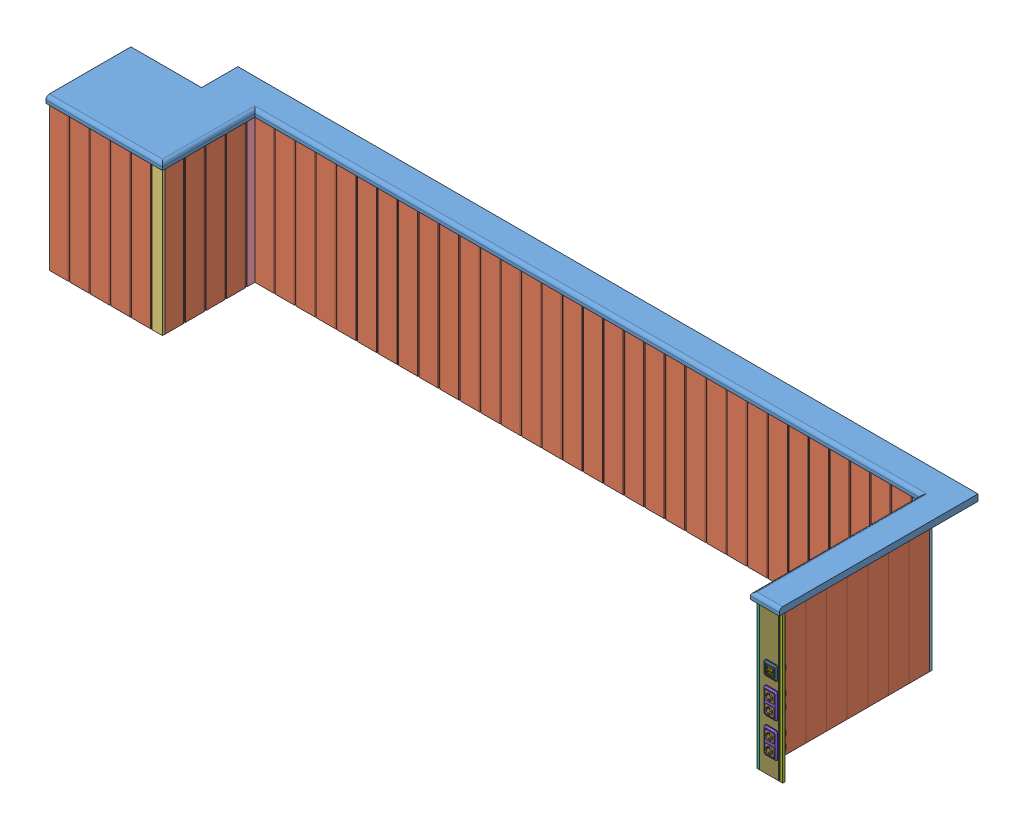
SolidWorks assembly Brüstung, configuration Standard. Lengths in mm.
Overall size (4774 900 1170).
129 component instances, 30 part files, 185 mates.
Components (placement in the parent):
- Platte-1: Platte [Standard] at (1989.1315 795.0064 4189) size (4774 38 1170)
- Wandbrett-1: Wandbrett [Standard] at (-2724.3685 795.0064 4876) x (1 0 0) z (0 0 -1) size (131 862 14)
- Wandbrett-2: Wandbrett [Standard] at (-2603.3685 795.0064 4876) x (1 0 0) z (0 0 -1) size (131 862 14)
- Wandbrett-3: Wandbrett [Standard] at (-2482.3685 795.0064 4876) x (1 0 0) z (0 0 -1) size (131 862 14)
- Wandbrett-4: Wandbrett [Standard] at (-2361.3685 795.0064 4876) x (1 0 0) z (0 0 -1) size (131 862 14)
- Wandbrett-Ecke1-1: Wandbrett-Ecke1 [Standard] at (-2119.3685 795.0064 4876) x (1 0 0) z (0 0 -1) size (61 862 14)
- Wandbrett-6: Wandbrett [Standard] at (-2125.8685 795.0064 4808.5) x (0 0 -1) z (-1 0 0) size (131 862 14)
- Wandbrett-7: Wandbrett [Standard] at (-2125.8685 795.0064 4687.5) x (0 0 -1) z (-1 0 0) size (131 862 14)
- Wandbrett-8: Wandbrett [Standard] at (-2125.8685 795.0064 4566.5) x (0 0 -1) z (-1 0 0) size (131 862 14)
- Wandbrett-9: Wandbrett [Standard] at (-2125.8685 795.0064 4445.5) x (0 0 -1) z (-1 0 0) size (131 862 14)
- Wandbrett-Ecke2-1: Wandbrett-Ecke2 [Standard] at (-2125.8685 795.0064 4324.5) x (0 0 -1) z (-1 0 0) size (60 862 14)
- Wandbrett-11: Wandbrett [Standard] at (-2058.3685 795.0064 4332) x (1 0 0) z (0 0 -1) size (131 862 14)
- Wandbrett-12: Wandbrett [Standard] at (-1937.3685 795.0064 4332) x (1 0 0) z (0 0 -1) size (131 862 14)
- Wandbrett-13: Wandbrett [Standard] at (-1816.3685 795.0064 4332) x (1 0 0) z (0 0 -1) size (131 862 14)
- Wandbrett-14: Wandbrett [Standard] at (-1695.3685 795.0064 4332) x (1 0 0) z (0 0 -1) size (131 862 14)
- Wandbrett-15: Wandbrett [Standard] at (-1574.3685 795.0064 4332) x (1 0 0) z (0 0 -1) size (131 862 14)
- Wandbrett-16: Wandbrett [Standard] at (-1453.3685 795.0064 4332) x (1 0 0) z (0 0 -1) size (131 862 14)
- Wandbrett-17: Wandbrett [Standard] at (-1332.3685 795.0064 4332) x (1 0 0) z (0 0 -1) size (131 862 14)
- Wandbrett-18: Wandbrett [Standard] at (-1211.3685 795.0064 4332) x (1 0 0) z (0 0 -1) size (131 862 14)
- Wandbrett-19: Wandbrett [Standard] at (-1090.3685 795.0064 4332) x (1 0 0) z (0 0 -1) size (131 862 14)
- Wandbrett-20: Wandbrett [Standard] at (-969.3685 795.0064 4332) x (1 0 0) z (0 0 -1) size (131 862 14)
- Wandbrett-21: Wandbrett [Standard] at (-848.3685 795.0064 4332) x (1 0 0) z (0 0 -1) size (131 862 14)
- Wandbrett-22: Wandbrett [Standard] at (-727.3685 795.0064 4332) x (1 0 0) z (0 0 -1) size (131 862 14)
- Wandbrett-23: Wandbrett [Standard] at (-606.3685 795.0064 4332) x (1 0 0) z (0 0 -1) size (131 862 14)
- Wandbrett-24: Wandbrett [Standard] at (-485.3685 795.0064 4332) x (1 0 0) z (0 0 -1) size (131 862 14)
- Wandbrett-25: Wandbrett [Standard] at (-364.3685 795.0064 4332) x (1 0 0) z (0 0 -1) size (131 862 14)
- Wandbrett-26: Wandbrett [Standard] at (-243.3685 795.0064 4332) x (1 0 0) z (0 0 -1) size (131 862 14)
- Wandbrett-27: Wandbrett [Standard] at (-122.3685 795.0064 4332) x (1 0 0) z (0 0 -1) size (131 862 14)
- Wandbrett-28: Wandbrett [Standard] at (-1.3685 795.0064 4332) x (1 0 0) z (0 0 -1) size (131 862 14)
- Wandbrett-29: Wandbrett [Standard] at (119.6315 795.0064 4332) x (1 0 0) z (0 0 -1) size (131 862 14)
- Wandbrett-30: Wandbrett [Standard] at (240.6315 795.0064 4332) x (1 0 0) z (0 0 -1) size (131 862 14)
- Wandbrett-31: Wandbrett [Standard] at (361.6315 795.0064 4332) x (1 0 0) z (0 0 -1) size (131 862 14)
- Wandbrett-32: Wandbrett [Standard] at (482.6315 795.0064 4332) x (1 0 0) z (0 0 -1) size (131 862 14)
- Wandbrett-33: Wandbrett [Standard] at (603.6315 795.0064 4332) x (1 0 0) z (0 0 -1) size (131 862 14)
- Wandbrett-34: Wandbrett [Standard] at (724.6315 795.0064 4332) x (1 0 0) z (0 0 -1) size (131 862 14)
- Wandbrett-35: Wandbrett [Standard] at (845.6315 795.0064 4332) x (1 0 0) z (0 0 -1) size (131 862 14)
- Wandbrett-36: Wandbrett [Standard] at (966.6315 795.0064 4332) x (1 0 0) z (0 0 -1) size (131 862 14)
- Wandbrett-37: Wandbrett [Standard] at (1087.6315 795.0064 4332) x (1 0 0) z (0 0 -1) size (131 862 14)
- Wandbrett-38: Wandbrett [Standard] at (1208.6315 795.0064 4332) x (1 0 0) z (0 0 -1) size (131 862 14)
- Wandbrett-39: Wandbrett [Standard] at (1329.6315 795.0064 4332) x (1 0 0) z (0 0 -1) size (131 862 14)
- Wandbrett-40: Wandbrett [Standard] at (1450.6315 795.0064 4332) x (1 0 0) z (0 0 -1) size (131 862 14)
- Wandbrett-41: Wandbrett [Standard] at (1571.6315 795.0064 4332) x (1 0 0) z (0 0 -1) size (131 862 14)
- Wandbrett-42: Wandbrett [Standard] at (1692.6315 795.0064 4332) x (1 0 0) z (0 0 -1) size (131 862 14)
- Wandbrett-43: Wandbrett [Standard] at (-2240.3685 795.0064 4876) x (1 0 0) z (0 0 -1) size (131 862 14)
- Wandbrett-Ecke3-1: Wandbrett-Ecke3 [Standard] at (1813.6315 795.0064 4332) x (1 0 0) z (0 0 -1) size (100 862 14)
- Wandbrett-44: Wandbrett [Standard] at (1846.1315 795.0064 4399.5) x (0 0 1) z (1 0 0) size (131 862 14)
- Wandbrett-45: Wandbrett [Standard] at (1846.1315 795.0064 4520.5) x (0 0 1) z (1 0 0) size (131 862 14)
- Wandbrett-46: Wandbrett [Standard] at (1846.1315 795.0064 4641.5) x (0 0 1) z (1 0 0) size (131 862 14)
- Wandbrett-47: Wandbrett [Standard] at (1846.1315 795.0064 4762.5) x (0 0 1) z (1 0 0) size (131 862 14)
- Wandbrett-48: Wandbrett [Standard] at (1846.1315 795.0064 4883.5) x (0 0 1) z (1 0 0) size (131 862 14)
- Wandbrett-49: Wandbrett [Standard] at (1846.1315 795.0064 5004.5) x (0 0 1) z (1 0 0) size (131 862 14)
- Wandbrett-50: Wandbrett [Standard] at (1846.1315 795.0064 5125.5) x (0 0 1) z (1 0 0) size (131 862 14)
- Wandbrett-51: Wandbrett [Standard] at (1846.1315 795.0064 5246.5) x (0 0 1) z (1 0 0) size (131 862 14)
- Wandbrett-Ecke4-1: Wandbrett-Ecke4 [Standard] at (1846.1315 795.0064 5367.5) x (0 0 1) z (1 0 0) size (32 862 14)
- Wandbrett-Ecke5-1: Wandbrett-Ecke5 [Standard] at (2034.6315 795.0064 5332) x (1 0 0) z (0 0 -1) size (15 862 14)
- Steckdose_2er-1: Steckdose_2er [Standard] at (1873.2124 150.5045 5350) x (0 -1 0) z (0 0 1) size (152.53 80.54 48.85)
  - Wandplatte_2er-1: Wandplatte_2er [Standard] at origin size (152.53 80.54 11)
  - Steckdose-1: Steckdose [Standard] at (58.6803 128.1202 -10.7714) x (1 0 0) z (0 -1 0) size (71 48.85 71)
    - Montageplatte.02-1: Montageplatte.02 [Standard] at (-129.6803 11 128.1202) x (1 0 0) z (0 1 0) size (71 71 18.97)
    - Halter-1: Halter [Standard] at (-129.6803 11 128.1202) x (1 0 0) z (0 1 0) size (45.97 31.9 15.37)
    - Kralle.04-1: Kralle.04 [Standard] at (-126.9942 12.4168 128.1202) x (0.996195 -0.087156 0) z (0.087156 0.996195 0) size (8.78 9 23.36)
    - Kralle.04-2: Kralle.04 [Standard] at (21.6299 12.4168 26.282) x (-0.996195 -0.087156 0) z (-0.087156 0.996195 0) size (8.78 9 23.36)
    - Buchse-1: Buchse [Standard] at (-129.6803 10.7714 128.1202) x (1 0 0) z (0 1 0) size (64.03 64.03 27)
    - Stromklemme_1.02-1: Stromklemme_1.02 [Standard] at (-129.6803 11 127.9932) x (1 0 0) z (0 1 0) size (8.38 19.82 12.51)
    - Stromklemme_2.02-1: Stromklemme_2.02 [Standard] at (-129.6803 11 127.9932) x (1 0 0) z (0 1 0) size (8.38 19.82 12.51)
    - Erdleiter-1: Erdleiter [Standard] at (-129.6803 11 128.1202) x (1 0 0) z (0 1 0) size (7.24 44.01 27.12)
  - Steckdose-2: Steckdose [Standard] at (129.6803 128.1202 -10.7714) x (1 0 0) z (0 -1 0) size (71 48.85 71)
    - Montageplatte.02-1: Montageplatte.02 [Standard] at (-129.6803 11 128.1202) x (1 0 0) z (0 1 0) size (71 71 18.97)
    - Halter-1: Halter [Standard] at (-129.6803 11 128.1202) x (1 0 0) z (0 1 0) size (45.97 31.9 15.37)
    - Kralle.04-1: Kralle.04 [Standard] at (-126.9942 12.4168 128.1202) x (0.996195 -0.087156 0) z (0.087156 0.996195 0) size (8.78 9 23.36)
    - Kralle.04-2: Kralle.04 [Standard] at (21.6299 12.4168 26.282) x (-0.996195 -0.087156 0) z (-0.087156 0.996195 0) size (8.78 9 23.36)
    - Buchse-1: Buchse [Standard] at (-129.6803 10.7714 128.1202) x (1 0 0) z (0 1 0) size (64.03 64.03 27)
    - Stromklemme_1.02-1: Stromklemme_1.02 [Standard] at (-129.6803 11 127.9932) x (1 0 0) z (0 1 0) size (8.38 19.82 12.51)
    - Stromklemme_2.02-1: Stromklemme_2.02 [Standard] at (-129.6803 11 127.9932) x (1 0 0) z (0 1 0) size (8.38 19.82 12.51)
    - Erdleiter-1: Erdleiter [Standard] at (-129.6803 11 128.1202) x (1 0 0) z (0 1 0) size (7.24 44.01 27.12)
- Steckdose_1er-RJ-1: Steckdose_1er-RJ [Standard] at (1922.84 484.4291 5275.7349) x (0 -1 0) z (0 0 1) size (81 80 25.23)
  - Steckdose-RJ45-1: Steckdose-RJ45 [Standard] at (18.9082 -0.7233 10.2377) size (54 54 25.23)
    - Buchse-RJ45-1: Buchse-RJ45 [Standard] at (-88.9836 -48.9043 64.0274) size (54 54 6)
    - 65864-1: 65864 [Default] at (-11.8405 9.7148 53.1274) size (17.49 15.42 25.23)
      - 65864_01-1: 65864_01 [Default] at origin size (9.69 0.75 13.83)
      - 65864_02-1: 65864_02 [Default] at origin size (9.44 0.68 13.83)
      - 65864_03-1: 65864_03 [Default] at origin size (9.69 0.61 13.84)
      - 65864_04-1: 65864_04 [Default] at origin size (9.44 0.54 13.83)
      - 65864_05-1: 65864_05 [Default] at origin size (9.69 0.54 13.82)
      - 65864_06-1: 65864_06 [Default] at origin size (9.44 0.6 13.83)
      - 65864_07-1: 65864_07 [Default] at origin size (9.69 0.68 13.83)
      - 65864_08-1: 65864_08 [Default] at origin size (9.44 0.75 13.83)
      - 65864_09-1: 65864_09 [Default] at origin size (17.11 15.1 23.65)
      - 65864_10-1: 65864_10 [Default] at origin size (6.36 10.31 6.36)
      - 65864_11-1: 65864_11 [Default] at origin size (17.49 15.42 25.23)
    - 65864-2: 65864 [Default] at (-11.8405 -5.6852 53.1274) size (17.49 15.42 25.23)
      - 65864_01-1: 65864_01 [Default] at origin size (9.69 0.75 13.83)
      - 65864_02-1: 65864_02 [Default] at origin size (9.44 0.68 13.83)
      - 65864_03-1: 65864_03 [Default] at origin size (9.69 0.61 13.84)
      - 65864_04-1: 65864_04 [Default] at origin size (9.44 0.54 13.83)
      - 65864_05-1: 65864_05 [Default] at origin size (9.69 0.54 13.82)
      - 65864_06-1: 65864_06 [Default] at origin size (9.44 0.6 13.83)
      - 65864_07-1: 65864_07 [Default] at origin size (9.69 0.68 13.83)
      - 65864_08-1: 65864_08 [Default] at origin size (9.44 0.75 13.83)
      - 65864_09-1: 65864_09 [Default] at origin size (17.11 15.1 23.65)
      - 65864_10-1: 65864_10 [Default] at origin size (6.36 10.31 6.36)
      - 65864_11-1: 65864_11 [Default] at origin size (17.49 15.42 25.23)
  - Wandplatte_1er-1: Wandplatte_1er [Standard] at (0.9246 -49.6276 74.2651) size (81 80 11.01)
- Steckdose_2er-2: Steckdose_2er [Standard] at (1873.2124 352.5045 5350) x (0 -1 0) z (0 0 1) size (152.53 80.54 48.85)
  - Wandplatte_2er-1: Wandplatte_2er [Standard] at origin size (152.53 80.54 11)
  - Steckdose-1: Steckdose [Standard] at (58.6803 128.1202 -10.7714) x (1 0 0) z (0 -1 0) size (71 48.85 71)
    - Montageplatte.02-1: Montageplatte.02 [Standard] at (-129.6803 11 128.1202) x (1 0 0) z (0 1 0) size (71 71 18.97)
    - Halter-1: Halter [Standard] at (-129.6803 11 128.1202) x (1 0 0) z (0 1 0) size (45.97 31.9 15.37)
    - Kralle.04-1: Kralle.04 [Standard] at (-126.9942 12.4168 128.1202) x (0.996195 -0.087156 0) z (0.087156 0.996195 0) size (8.78 9 23.36)
    - Kralle.04-2: Kralle.04 [Standard] at (21.6299 12.4168 26.282) x (-0.996195 -0.087156 0) z (-0.087156 0.996195 0) size (8.78 9 23.36)
    - Buchse-1: Buchse [Standard] at (-129.6803 10.7714 128.1202) x (1 0 0) z (0 1 0) size (64.03 64.03 27)
    - Stromklemme_1.02-1: Stromklemme_1.02 [Standard] at (-129.6803 11 127.9932) x (1 0 0) z (0 1 0) size (8.38 19.82 12.51)
    - Stromklemme_2.02-1: Stromklemme_2.02 [Standard] at (-129.6803 11 127.9932) x (1 0 0) z (0 1 0) size (8.38 19.82 12.51)
    - Erdleiter-1: Erdleiter [Standard] at (-129.6803 11 128.1202) x (1 0 0) z (0 1 0) size (7.24 44.01 27.12)
  - Steckdose-2: Steckdose [Standard] at (129.6803 128.1202 -10.7714) x (1 0 0) z (0 -1 0) size (71 48.85 71)
    - Montageplatte.02-1: Montageplatte.02 [Standard] at (-129.6803 11 128.1202) x (1 0 0) z (0 1 0) size (71 71 18.97)
    - Halter-1: Halter [Standard] at (-129.6803 11 128.1202) x (1 0 0) z (0 1 0) size (45.97 31.9 15.37)
    - Kralle.04-1: Kralle.04 [Standard] at (-126.9942 12.4168 128.1202) x (0.996195 -0.087156 0) z (0.087156 0.996195 0) size (8.78 9 23.36)
    - Kralle.04-2: Kralle.04 [Standard] at (21.6299 12.4168 26.282) x (-0.996195 -0.087156 0) z (-0.087156 0.996195 0) size (8.78 9 23.36)
    - Buchse-1: Buchse [Standard] at (-129.6803 10.7714 128.1202) x (1 0 0) z (0 1 0) size (64.03 64.03 27)
    - Stromklemme_1.02-1: Stromklemme_1.02 [Standard] at (-129.6803 11 127.9932) x (1 0 0) z (0 1 0) size (8.38 19.82 12.51)
    - Stromklemme_2.02-1: Stromklemme_2.02 [Standard] at (-129.6803 11 127.9932) x (1 0 0) z (0 1 0) size (8.38 19.82 12.51)
    - Erdleiter-1: Erdleiter [Standard] at (-129.6803 11 128.1202) x (1 0 0) z (0 1 0) size (7.24 44.01 27.12)
- Hohlwanddose-1: Hohlwanddose [Standard] at (1924.1315 477.4581 5340) x (0 0 -1) z (1 0 0) size (60.7 71 71)
- Hohlwanddose-2: Hohlwanddose [Standard] at (1924.1315 346.5064 5340) x (0 0 -1) z (1 0 0) size (60.7 71 71)
- Hohlwanddose-3: Hohlwanddose [Standard] at (1924.1315 275.5064 5340) x (0 0 -1) z (1 0 0) size (60.7 71 71)
- Hohlwanddose-4: Hohlwanddose [Standard] at (1924.1315 144.5064 5340) x (0 0 -1) z (1 0 0) size (60.7 71 71)
- Hohlwanddose-5: Hohlwanddose [Standard] at (1924.1315 73.5064 5340) x (0 0 -1) z (1 0 0) size (60.7 71 71)
- Wandbrett-Dosen1-1: Wandbrett-Dosen1 [Standard] at (1913.6315 795.0064 5332) x (1 0 0) z (0 0 -1) size (131 862 14)
Mates (geometry in assembly coordinates):
- Deckungsgleich1: coincident anti-aligned: plane of Platte-1 through (1989.1315 795.0064 4189) normal (0 -1 0); plane of Wandbrett-1 through (-2674.8685 795.0064 4879) normal (0 1 0)
- Deckungsgleich2: coincident anti-aligned: plane of Platte-1 through (1989.1315 795.0064 4189) normal (0 -1 0); plane of Wandbrett-2 through (-2553.8685 795.0064 4879) normal (0 1 0)
- Deckungsgleich3: coincident anti-aligned: plane of Platte-1 through (1989.1315 795.0064 4189) normal (0 -1 0); plane of Wandbrett-3 through (-2432.8685 795.0064 4879) normal (0 1 0)
- Deckungsgleich4: coincident anti-aligned: plane of Platte-1 through (1989.1315 795.0064 4189) normal (0 -1 0); plane of Wandbrett-4 through (-2311.8685 795.0064 4879) normal (0 1 0)
- Parallel1: parallel aligned: plane of Platte-1 through (-2784.8685 833.0064 4903) normal (0 0 1); plane of Wandbrett-1 through (-2674.8685 -66.9936 4883) normal (0 0 1)
- Abstand2: distance = 20 mm aligned: plane of Wandbrett-1 through (-2674.8685 -66.9936 4883) normal (0 0 1); plane of Platte-1 through (-2784.8685 833.0064 4903) normal (0 0 1)
- Deckungsgleich9: coincident aligned: plane of Platte-1 through (-2784.8685 833.0064 4903) normal (-1 0 0); plane of Wandbrett-1 through (-2784.8685 -66.9936 4869) normal (-1 0 0)
- Deckungsgleich10: coincident anti-aligned: plane of Wandbrett-1 through (-2663.8685 -66.9936 4878) normal (0 0 1); plane of Wandbrett-2 through (-2653.8685 -66.9936 4878) normal (0 0 -1)
- Deckungsgleich11: coincident anti-aligned: plane of Wandbrett-2 through (-2542.8685 -66.9936 4878) normal (0 0 1); plane of Wandbrett-3 through (-2532.8685 -66.9936 4878) normal (0 0 -1)
- Deckungsgleich12: coincident anti-aligned: plane of Wandbrett-3 through (-2421.8685 -66.9936 4878) normal (0 0 1); plane of Wandbrett-4 through (-2411.8685 -66.9936 4878) normal (0 0 -1)
- Deckungsgleich14: coincident anti-aligned: plane of Wandbrett-1 through (-2653.8685 -66.9936 4878) normal (1 0 0); plane of Wandbrett-2 through (-2653.8685 -66.9936 4874) normal (-1 0 0)
- Deckungsgleich15: coincident anti-aligned: plane of Wandbrett-2 through (-2532.8685 -66.9936 4878) normal (1 0 0); plane of Wandbrett-3 through (-2532.8685 -66.9936 4874) normal (-1 0 0)
- Deckungsgleich16: coincident anti-aligned: plane of Wandbrett-3 through (-2411.8685 -66.9936 4878) normal (1 0 0); plane of Wandbrett-4 through (-2411.8685 -66.9936 4874) normal (-1 0 0)
- Deckungsgleich18: coincident anti-aligned: plane of Platte-1 through (1989.1315 795.0064 4189) normal (0 -1 0); plane of Wandbrett-Ecke1-1 through (-2069.8685 795.0064 4879) normal (0 1 0)
- Deckungsgleich21: coincident anti-aligned: plane of Platte-1 through (1989.1315 795.0064 4189) normal (0 -1 0); plane of Wandbrett-6 through (-2122.8685 795.0064 4759) normal (0 1 0)
- Deckungsgleich22: coincident anti-aligned: plane of Platte-1 through (1989.1315 795.0064 4189) normal (0 -1 0); plane of Wandbrett-7 through (-2122.8685 795.0064 4638) normal (0 1 0)
- Deckungsgleich23: coincident anti-aligned: plane of Platte-1 through (1989.1315 795.0064 4189) normal (0 -1 0); plane of Wandbrett-8 through (-2122.8685 795.0064 4517) normal (0 1 0)
- Deckungsgleich24: coincident anti-aligned: plane of Platte-1 through (1989.1315 795.0064 4189) normal (0 -1 0); plane of Wandbrett-9 through (-2122.8685 795.0064 4396) normal (0 1 0)
- Deckungsgleich26: coincident anti-aligned: plane of Wandbrett-Ecke1-1 through (-2058.8685 -66.9936 4869) normal (0 0 -1); plane of Wandbrett-6 through (-2132.8685 -66.9936 4869) normal (0 0 1)
- Deckungsgleich27: coincident aligned: plane of Wandbrett-Ecke1-1 through (-2118.8685 -204.9936 4869) normal (1 0 0); plane of Wandbrett-6 through (-2118.8685 -66.9936 4759) normal (1 0 0)
- Deckungsgleich28: coincident anti-aligned: plane of Wandbrett-6 through (-2123.8685 -66.9936 4748) normal (1 0 0); plane of Wandbrett-7 through (-2123.8685 -66.9936 4738) normal (-1 0 0)
- Deckungsgleich29: coincident anti-aligned: plane of Wandbrett-7 through (-2123.8685 -66.9936 4627) normal (1 0 0); plane of Wandbrett-8 through (-2123.8685 -66.9936 4617) normal (-1 0 0)
- Deckungsgleich30: coincident anti-aligned: plane of Wandbrett-8 through (-2123.8685 -66.9936 4506) normal (1 0 0); plane of Wandbrett-9 through (-2123.8685 -66.9936 4496) normal (-1 0 0)
- Deckungsgleich32: coincident anti-aligned: plane of Wandbrett-6 through (-2123.8685 -66.9936 4738) normal (0 0 -1); plane of Wandbrett-7 through (-2127.8685 -66.9936 4738) normal (0 0 1)
- Deckungsgleich33: coincident anti-aligned: plane of Wandbrett-7 through (-2123.8685 -66.9936 4617) normal (0 0 -1); plane of Wandbrett-8 through (-2127.8685 -66.9936 4617) normal (0 0 1)
- Deckungsgleich34: coincident anti-aligned: plane of Wandbrett-8 through (-2123.8685 -66.9936 4496) normal (0 0 -1); plane of Wandbrett-9 through (-2127.8685 -66.9936 4496) normal (0 0 1)
- Deckungsgleich36: coincident anti-aligned: plane of Platte-1 through (1989.1315 795.0064 4189) normal (0 -1 0); plane of Wandbrett-Ecke2-1 through (-2122.8685 795.0064 4275) normal (0 1 0)
- Deckungsgleich37: coincident anti-aligned: plane of Wandbrett-9 through (-2123.8685 -66.9936 4385) normal (1 0 0); plane of Wandbrett-Ecke2-1 through (-2123.8685 -66.9936 4375) normal (-1 0 0)
- Deckungsgleich38: coincident anti-aligned: plane of Wandbrett-9 through (-2123.8685 -66.9936 4375) normal (0 0 -1); plane of Wandbrett-Ecke2-1 through (-2127.8685 -66.9936 4375) normal (0 0 1)
- Deckungsgleich39: coincident anti-aligned: plane of Platte-1 through (1989.1315 795.0064 4189) normal (0 -1 0); plane of Wandbrett-11 through (-2008.8685 795.0064 4335) normal (0 1 0)
- Deckungsgleich40: coincident anti-aligned: plane of Platte-1 through (1989.1315 795.0064 4189) normal (0 -1 0); plane of Wandbrett-12 through (-1887.8685 795.0064 4335) normal (0 1 0)
- Deckungsgleich41: coincident anti-aligned: plane of Platte-1 through (1989.1315 795.0064 4189) normal (0 -1 0); plane of Wandbrett-13 through (-1766.8685 795.0064 4335) normal (0 1 0)
- Deckungsgleich42: coincident anti-aligned: plane of Platte-1 through (1989.1315 795.0064 4189) normal (0 -1 0); plane of Wandbrett-14 through (-1645.8685 795.0064 4335) normal (0 1 0)
- Deckungsgleich43: coincident anti-aligned: plane of Platte-1 through (1989.1315 795.0064 4189) normal (0 -1 0); plane of Wandbrett-15 through (-1524.8685 795.0064 4335) normal (0 1 0)
- Deckungsgleich44: coincident anti-aligned: plane of Platte-1 through (1989.1315 795.0064 4189) normal (0 -1 0); plane of Wandbrett-16 through (-1403.8685 795.0064 4335) normal (0 1 0)
- Deckungsgleich45: coincident anti-aligned: plane of Platte-1 through (1989.1315 795.0064 4189) normal (0 -1 0); plane of Wandbrett-17 through (-1282.8685 795.0064 4335) normal (0 1 0)
- Deckungsgleich46: coincident anti-aligned: plane of Platte-1 through (1989.1315 795.0064 4189) normal (0 -1 0); plane of Wandbrett-18 through (-1161.8685 795.0064 4335) normal (0 1 0)
- Deckungsgleich47: coincident anti-aligned: plane of Platte-1 through (1989.1315 795.0064 4189) normal (0 -1 0); plane of Wandbrett-19 through (-1040.8685 795.0064 4335) normal (0 1 0)
- Deckungsgleich48: coincident anti-aligned: plane of Platte-1 through (1989.1315 795.0064 4189) normal (0 -1 0); plane of Wandbrett-20 through (-919.8685 795.0064 4335) normal (0 1 0)
- Deckungsgleich49: coincident anti-aligned: plane of Platte-1 through (1989.1315 795.0064 4189) normal (0 -1 0); plane of Wandbrett-21 through (-798.8685 795.0064 4335) normal (0 1 0)
- Deckungsgleich50: coincident anti-aligned: plane of Platte-1 through (1989.1315 795.0064 4189) normal (0 -1 0); plane of Wandbrett-22 through (-677.8685 795.0064 4335) normal (0 1 0)
- Deckungsgleich51: coincident anti-aligned: plane of Platte-1 through (1989.1315 795.0064 4189) normal (0 -1 0); plane of Wandbrett-23 through (-556.8685 795.0064 4335) normal (0 1 0)
- Deckungsgleich52: coincident anti-aligned: plane of Platte-1 through (1989.1315 795.0064 4189) normal (0 -1 0); plane of Wandbrett-24 through (-435.8685 795.0064 4335) normal (0 1 0)
- Deckungsgleich53: coincident anti-aligned: plane of Platte-1 through (1989.1315 795.0064 4189) normal (0 -1 0); plane of Wandbrett-25 through (-314.8685 795.0064 4335) normal (0 1 0)
- Deckungsgleich54: coincident anti-aligned: plane of Platte-1 through (1989.1315 795.0064 4189) normal (0 -1 0); plane of Wandbrett-26 through (-193.8685 795.0064 4335) normal (0 1 0)
- Deckungsgleich55: coincident anti-aligned: plane of Platte-1 through (1989.1315 795.0064 4189) normal (0 -1 0); plane of Wandbrett-27 through (-72.8685 795.0064 4335) normal (0 1 0)
- Deckungsgleich56: coincident anti-aligned: plane of Platte-1 through (1989.1315 795.0064 4189) normal (0 -1 0); plane of Wandbrett-28 through (48.1315 795.0064 4335) normal (0 1 0)
- Deckungsgleich57: coincident anti-aligned: plane of Platte-1 through (1989.1315 795.0064 4189) normal (0 -1 0); plane of Wandbrett-29 through (169.1315 795.0064 4335) normal (0 1 0)
- Deckungsgleich58: coincident anti-aligned: plane of Platte-1 through (1989.1315 795.0064 4189) normal (0 -1 0); plane of Wandbrett-30 through (290.1315 795.0064 4335) normal (0 1 0)
- Deckungsgleich59: coincident anti-aligned: plane of Platte-1 through (1989.1315 795.0064 4189) normal (0 -1 0); plane of Wandbrett-31 through (411.1315 795.0064 4335) normal (0 1 0)
- Deckungsgleich60: coincident anti-aligned: plane of Platte-1 through (1989.1315 795.0064 4189) normal (0 -1 0); plane of Wandbrett-32 through (532.1315 795.0064 4335) normal (0 1 0)
- Deckungsgleich61: coincident anti-aligned: plane of Platte-1 through (1989.1315 795.0064 4189) normal (0 -1 0); plane of Wandbrett-33 through (653.1315 795.0064 4335) normal (0 1 0)
- Deckungsgleich62: coincident anti-aligned: plane of Platte-1 through (1989.1315 795.0064 4189) normal (0 -1 0); plane of Wandbrett-34 through (774.1315 795.0064 4335) normal (0 1 0)
- Deckungsgleich63: coincident anti-aligned: plane of Platte-1 through (1989.1315 795.0064 4189) normal (0 -1 0); plane of Wandbrett-35 through (895.1315 795.0064 4335) normal (0 1 0)
- Deckungsgleich64: coincident anti-aligned: plane of Platte-1 through (1989.1315 795.0064 4189) normal (0 -1 0); plane of Wandbrett-36 through (1016.1315 795.0064 4335) normal (0 1 0)
- Deckungsgleich65: coincident anti-aligned: plane of Platte-1 through (1989.1315 795.0064 4189) normal (0 -1 0); plane of Wandbrett-37 through (1137.1315 795.0064 4335) normal (0 1 0)
- Deckungsgleich66: coincident anti-aligned: plane of Platte-1 through (1989.1315 795.0064 4189) normal (0 -1 0); plane of Wandbrett-38 through (1258.1315 795.0064 4335) normal (0 1 0)
- Deckungsgleich67: coincident anti-aligned: plane of Platte-1 through (1989.1315 795.0064 4189) normal (0 -1 0); plane of Wandbrett-39 through (1379.1315 795.0064 4335) normal (0 1 0)
- Deckungsgleich68: coincident anti-aligned: plane of Platte-1 through (1989.1315 795.0064 4189) normal (0 -1 0); plane of Wandbrett-40 through (1500.1315 795.0064 4335) normal (0 1 0)
- Deckungsgleich69: coincident anti-aligned: plane of Platte-1 through (1989.1315 795.0064 4189) normal (0 -1 0); plane of Wandbrett-41 through (1621.1315 795.0064 4335) normal (0 1 0)
- Deckungsgleich70: coincident anti-aligned: plane of Platte-1 through (1989.1315 795.0064 4189) normal (0 -1 0); plane of Wandbrett-42 through (1742.1315 795.0064 4335) normal (0 1 0)
- Deckungsgleich71: coincident anti-aligned: plane of Wandbrett-Ecke2-1 through (-2118.8685 -66.9936 4275) normal (1 0 0); plane of Wandbrett-11 through (-2118.8685 -66.9936 4334) normal (-1 0 0)
- Deckungsgleich72: coincident anti-aligned: plane of Wandbrett-11 through (-1997.8685 -66.9936 4334) normal (0 0 1); plane of Wandbrett-12 through (-1987.8685 -66.9936 4334) normal (0 0 -1)
- Deckungsgleich73: coincident anti-aligned: plane of Wandbrett-12 through (-1876.8685 -66.9936 4334) normal (0 0 1); plane of Wandbrett-13 through (-1866.8685 -66.9936 4334) normal (0 0 -1)
- Deckungsgleich74: coincident anti-aligned: plane of Wandbrett-13 through (-1755.8685 -66.9936 4334) normal (0 0 1); plane of Wandbrett-14 through (-1745.8685 -66.9936 4334) normal (0 0 -1)
- Deckungsgleich75: coincident anti-aligned: plane of Wandbrett-14 through (-1634.8685 -66.9936 4334) normal (0 0 1); plane of Wandbrett-15 through (-1624.8685 -66.9936 4334) normal (0 0 -1)
- Deckungsgleich76: coincident anti-aligned: plane of Wandbrett-15 through (-1513.8685 -66.9936 4334) normal (0 0 1); plane of Wandbrett-16 through (-1503.8685 -66.9936 4334) normal (0 0 -1)
- Deckungsgleich77: coincident anti-aligned: plane of Wandbrett-16 through (-1392.8685 -66.9936 4334) normal (0 0 1); plane of Wandbrett-17 through (-1382.8685 -66.9936 4334) normal (0 0 -1)
- Deckungsgleich78: coincident anti-aligned: plane of Wandbrett-17 through (-1271.8685 -66.9936 4334) normal (0 0 1); plane of Wandbrett-18 through (-1261.8685 -66.9936 4334) normal (0 0 -1)
- Deckungsgleich79: coincident anti-aligned: plane of Wandbrett-18 through (-1150.8685 -66.9936 4334) normal (0 0 1); plane of Wandbrett-19 through (-1140.8685 -66.9936 4334) normal (0 0 -1)
- Deckungsgleich80: coincident anti-aligned: plane of Wandbrett-19 through (-1029.8685 -66.9936 4334) normal (0 0 1); plane of Wandbrett-20 through (-1019.8685 -66.9936 4334) normal (0 0 -1)
- Deckungsgleich81: coincident anti-aligned: plane of Wandbrett-20 through (-908.8685 -66.9936 4334) normal (0 0 1); plane of Wandbrett-21 through (-898.8685 -66.9936 4334) normal (0 0 -1)
- Deckungsgleich82: coincident anti-aligned: plane of Wandbrett-21 through (-787.8685 -66.9936 4334) normal (0 0 1); plane of Wandbrett-22 through (-777.8685 -66.9936 4334) normal (0 0 -1)
- Deckungsgleich83: coincident anti-aligned: plane of Wandbrett-22 through (-666.8685 -66.9936 4334) normal (0 0 1); plane of Wandbrett-23 through (-656.8685 -66.9936 4334) normal (0 0 -1)
- Deckungsgleich84: coincident anti-aligned: plane of Wandbrett-23 through (-545.8685 -66.9936 4334) normal (0 0 1); plane of Wandbrett-24 through (-535.8685 -66.9936 4334) normal (0 0 -1)
- Deckungsgleich85: coincident anti-aligned: plane of Wandbrett-24 through (-424.8685 -66.9936 4334) normal (0 0 1); plane of Wandbrett-25 through (-414.8685 -66.9936 4334) normal (0 0 -1)
- Deckungsgleich86: coincident anti-aligned: plane of Wandbrett-25 through (-303.8685 -66.9936 4334) normal (0 0 1); plane of Wandbrett-26 through (-293.8685 -66.9936 4334) normal (0 0 -1)
- Deckungsgleich87: coincident anti-aligned: plane of Wandbrett-26 through (-182.8685 -66.9936 4334) normal (0 0 1); plane of Wandbrett-27 through (-172.8685 -66.9936 4334) normal (0 0 -1)
- Deckungsgleich88: coincident anti-aligned: plane of Wandbrett-27 through (-61.8685 -66.9936 4334) normal (0 0 1); plane of Wandbrett-28 through (-51.8685 -66.9936 4334) normal (0 0 -1)
- Deckungsgleich90: coincident anti-aligned: plane of Wandbrett-28 through (59.1315 -66.9936 4334) normal (0 0 1); plane of Wandbrett-29 through (69.1315 -66.9936 4334) normal (0 0 -1)
- Deckungsgleich91: coincident anti-aligned: plane of Wandbrett-29 through (180.1315 -66.9936 4334) normal (0 0 1); plane of Wandbrett-30 through (190.1315 -66.9936 4334) normal (0 0 -1)
- Deckungsgleich92: coincident anti-aligned: plane of Wandbrett-30 through (301.1315 -66.9936 4334) normal (0 0 1); plane of Wandbrett-31 through (311.1315 -66.9936 4334) normal (0 0 -1)
- Deckungsgleich93: coincident anti-aligned: plane of Wandbrett-31 through (422.1315 -66.9936 4334) normal (0 0 1); plane of Wandbrett-32 through (432.1315 -66.9936 4334) normal (0 0 -1)
- Deckungsgleich94: coincident anti-aligned: plane of Wandbrett-32 through (543.1315 -66.9936 4334) normal (0 0 1); plane of Wandbrett-33 through (553.1315 -66.9936 4334) normal (0 0 -1)
- Deckungsgleich95: coincident anti-aligned: plane of Wandbrett-33 through (664.1315 -66.9936 4334) normal (0 0 1); plane of Wandbrett-34 through (674.1315 -66.9936 4334) normal (0 0 -1)
- Deckungsgleich96: coincident anti-aligned: plane of Wandbrett-34 through (785.1315 -66.9936 4334) normal (0 0 1); plane of Wandbrett-35 through (795.1315 -66.9936 4334) normal (0 0 -1)
- Deckungsgleich97: coincident anti-aligned: plane of Wandbrett-35 through (906.1315 -66.9936 4334) normal (0 0 1); plane of Wandbrett-36 through (916.1315 -66.9936 4334) normal (0 0 -1)
- Deckungsgleich98: coincident anti-aligned: plane of Wandbrett-36 through (1027.1315 -66.9936 4334) normal (0 0 1); plane of Wandbrett-37 through (1037.1315 -66.9936 4334) normal (0 0 -1)
- Deckungsgleich99: coincident anti-aligned: plane of Wandbrett-37 through (1148.1315 -66.9936 4334) normal (0 0 1); plane of Wandbrett-38 through (1158.1315 -66.9936 4334) normal (0 0 -1)
- Deckungsgleich100: coincident anti-aligned: plane of Wandbrett-38 through (1269.1315 -66.9936 4334) normal (0 0 1); plane of Wandbrett-39 through (1279.1315 -66.9936 4334) normal (0 0 -1)
- Deckungsgleich101: coincident anti-aligned: plane of Wandbrett-39 through (1390.1315 -66.9936 4334) normal (0 0 1); plane of Wandbrett-40 through (1400.1315 -66.9936 4334) normal (0 0 -1)
- Deckungsgleich102: coincident anti-aligned: plane of Wandbrett-40 through (1511.1315 -66.9936 4334) normal (0 0 1); plane of Wandbrett-41 through (1521.1315 -66.9936 4334) normal (0 0 -1)
- Deckungsgleich103: coincident anti-aligned: plane of Wandbrett-41 through (1632.1315 -66.9936 4334) normal (0 0 1); plane of Wandbrett-42 through (1642.1315 -66.9936 4334) normal (0 0 -1)
- Deckungsgleich104: coincident aligned: plane of Wandbrett-Ecke2-1 through (-2118.8685 -204.9936 4325) normal (0 0 -1); plane of Wandbrett-11 through (-1997.8685 -66.9936 4325) normal (0 0 -1)
- Deckungsgleich105: coincident anti-aligned: plane of Wandbrett-11 through (-1987.8685 -66.9936 4334) normal (1 0 0); plane of Wandbrett-12 through (-1987.8685 -66.9936 4330) normal (-1 0 0)
- Deckungsgleich106: coincident anti-aligned: plane of Wandbrett-12 through (-1866.8685 -66.9936 4334) normal (1 0 0); plane of Wandbrett-13 through (-1866.8685 -66.9936 4330) normal (-1 0 0)
- Deckungsgleich107: coincident anti-aligned: plane of Wandbrett-13 through (-1745.8685 -66.9936 4334) normal (1 0 0); plane of Wandbrett-14 through (-1745.8685 -66.9936 4330) normal (-1 0 0)
- Deckungsgleich108: coincident anti-aligned: plane of Wandbrett-14 through (-1624.8685 -66.9936 4334) normal (1 0 0); plane of Wandbrett-15 through (-1624.8685 -66.9936 4330) normal (-1 0 0)
- Deckungsgleich109: coincident anti-aligned: plane of Wandbrett-15 through (-1503.8685 -66.9936 4334) normal (1 0 0); plane of Wandbrett-16 through (-1503.8685 -66.9936 4330) normal (-1 0 0)
- Deckungsgleich110: coincident anti-aligned: plane of Wandbrett-16 through (-1382.8685 -66.9936 4334) normal (1 0 0); plane of Wandbrett-17 through (-1382.8685 -66.9936 4330) normal (-1 0 0)
- Deckungsgleich111: coincident anti-aligned: plane of Wandbrett-17 through (-1261.8685 -66.9936 4334) normal (1 0 0); plane of Wandbrett-18 through (-1261.8685 -66.9936 4330) normal (-1 0 0)
- Deckungsgleich112: coincident anti-aligned: plane of Wandbrett-18 through (-1140.8685 -66.9936 4334) normal (1 0 0); plane of Wandbrett-19 through (-1140.8685 -66.9936 4330) normal (-1 0 0)
- Deckungsgleich113: coincident anti-aligned: plane of Wandbrett-19 through (-1019.8685 -66.9936 4334) normal (1 0 0); plane of Wandbrett-20 through (-1019.8685 -66.9936 4330) normal (-1 0 0)
- Deckungsgleich114: coincident anti-aligned: plane of Wandbrett-20 through (-898.8685 -66.9936 4334) normal (1 0 0); plane of Wandbrett-21 through (-898.8685 -66.9936 4330) normal (-1 0 0)
- Deckungsgleich115: coincident anti-aligned: plane of Wandbrett-21 through (-777.8685 -66.9936 4334) normal (1 0 0); plane of Wandbrett-22 through (-777.8685 -66.9936 4330) normal (-1 0 0)
- Deckungsgleich117: coincident anti-aligned: plane of Wandbrett-22 through (-656.8685 -66.9936 4334) normal (1 0 0); plane of Wandbrett-23 through (-656.8685 -66.9936 4330) normal (-1 0 0)
- Deckungsgleich118: coincident anti-aligned: plane of Wandbrett-23 through (-535.8685 -66.9936 4334) normal (1 0 0); plane of Wandbrett-24 through (-535.8685 -66.9936 4330) normal (-1 0 0)
- Deckungsgleich119: coincident anti-aligned: plane of Wandbrett-24 through (-414.8685 -66.9936 4334) normal (1 0 0); plane of Wandbrett-25 through (-414.8685 -66.9936 4330) normal (-1 0 0)
- Deckungsgleich121: coincident anti-aligned: plane of Wandbrett-25 through (-293.8685 -66.9936 4334) normal (1 0 0); plane of Wandbrett-26 through (-293.8685 -66.9936 4330) normal (-1 0 0)
- Deckungsgleich122: coincident anti-aligned: plane of Wandbrett-26 through (-172.8685 -66.9936 4334) normal (1 0 0); plane of Wandbrett-27 through (-172.8685 -66.9936 4330) normal (-1 0 0)
- Deckungsgleich123: coincident anti-aligned: plane of Wandbrett-27 through (-51.8685 -66.9936 4334) normal (1 0 0); plane of Wandbrett-28 through (-51.8685 -66.9936 4330) normal (-1 0 0)
- Deckungsgleich124: coincident anti-aligned: plane of Wandbrett-28 through (69.1315 -66.9936 4334) normal (1 0 0); plane of Wandbrett-29 through (69.1315 -66.9936 4330) normal (-1 0 0)
- Deckungsgleich125: coincident anti-aligned: plane of Wandbrett-29 through (190.1315 -66.9936 4334) normal (1 0 0); plane of Wandbrett-30 through (190.1315 -66.9936 4330) normal (-1 0 0)
- Deckungsgleich126: coincident anti-aligned: plane of Wandbrett-30 through (311.1315 -66.9936 4334) normal (1 0 0); plane of Wandbrett-31 through (311.1315 -66.9936 4330) normal (-1 0 0)
- Deckungsgleich127: coincident anti-aligned: plane of Wandbrett-31 through (432.1315 -66.9936 4334) normal (1 0 0); plane of Wandbrett-32 through (432.1315 -66.9936 4330) normal (-1 0 0)
- Deckungsgleich128: coincident anti-aligned: plane of Wandbrett-32 through (553.1315 -66.9936 4334) normal (1 0 0); plane of Wandbrett-33 through (553.1315 -66.9936 4330) normal (-1 0 0)
- Deckungsgleich129: coincident anti-aligned: plane of Wandbrett-33 through (674.1315 -66.9936 4334) normal (1 0 0); plane of Wandbrett-34 through (674.1315 -66.9936 4330) normal (-1 0 0)
- Deckungsgleich130: coincident anti-aligned: plane of Wandbrett-34 through (795.1315 -66.9936 4334) normal (1 0 0); plane of Wandbrett-35 through (795.1315 -66.9936 4330) normal (-1 0 0)
- Deckungsgleich131: coincident anti-aligned: plane of Wandbrett-35 through (916.1315 -66.9936 4334) normal (1 0 0); plane of Wandbrett-36 through (916.1315 -66.9936 4330) normal (-1 0 0)
- Deckungsgleich132: coincident anti-aligned: plane of Wandbrett-36 through (1037.1315 -66.9936 4334) normal (1 0 0); plane of Wandbrett-37 through (1037.1315 -66.9936 4330) normal (-1 0 0)
- Deckungsgleich133: coincident anti-aligned: plane of Wandbrett-37 through (1158.1315 -66.9936 4334) normal (1 0 0); plane of Wandbrett-38 through (1158.1315 -66.9936 4330) normal (-1 0 0)
- Deckungsgleich136: coincident anti-aligned: plane of Wandbrett-38 through (1279.1315 -66.9936 4334) normal (1 0 0); plane of Wandbrett-39 through (1279.1315 -66.9936 4330) normal (-1 0 0)
- Deckungsgleich137: coincident anti-aligned: plane of Wandbrett-39 through (1400.1315 -66.9936 4334) normal (1 0 0); plane of Wandbrett-40 through (1400.1315 -66.9936 4330) normal (-1 0 0)
- Deckungsgleich138: coincident anti-aligned: plane of Wandbrett-40 through (1521.1315 -66.9936 4334) normal (1 0 0); plane of Wandbrett-41 through (1521.1315 -66.9936 4330) normal (-1 0 0)
- Deckungsgleich139: coincident anti-aligned: plane of Wandbrett-41 through (1642.1315 -66.9936 4334) normal (1 0 0); plane of Wandbrett-42 through (1642.1315 -66.9936 4330) normal (-1 0 0)
- Deckungsgleich140: coincident anti-aligned: plane of Platte-1 through (1989.1315 795.0064 4189) normal (0 -1 0); plane of Wandbrett-43 through (-2190.8685 795.0064 4879) normal (0 1 0)
- Deckungsgleich143: coincident anti-aligned: plane of Platte-1 through (1989.1315 795.0064 4189) normal (0 -1 0); plane of Wandbrett-Ecke3-1 through (1863.1315 795.0064 4335) normal (0 1 0)
- Deckungsgleich156: coincident anti-aligned: plane of Platte-1 through (1989.1315 795.0064 4189) normal (0 -1 0); plane of Wandbrett-44 through (1843.1315 795.0064 4449) normal (0 1 0)
- Deckungsgleich157: coincident anti-aligned: plane of Platte-1 through (1989.1315 795.0064 4189) normal (0 -1 0); plane of Wandbrett-45 through (1843.1315 795.0064 4570) normal (0 1 0)
- Deckungsgleich158: coincident anti-aligned: plane of Platte-1 through (1989.1315 795.0064 4189) normal (0 -1 0); plane of Wandbrett-46 through (1843.1315 795.0064 4691) normal (0 1 0)
- Deckungsgleich159: coincident anti-aligned: plane of Platte-1 through (1989.1315 795.0064 4189) normal (0 -1 0); plane of Wandbrett-47 through (1843.1315 795.0064 4812) normal (0 1 0)
- Deckungsgleich160: coincident anti-aligned: plane of Platte-1 through (1989.1315 795.0064 4189) normal (0 -1 0); plane of Wandbrett-48 through (1843.1315 795.0064 4933) normal (0 1 0)
- Deckungsgleich161: coincident anti-aligned: plane of Platte-1 through (1989.1315 795.0064 4189) normal (0 -1 0); plane of Wandbrett-49 through (1843.1315 795.0064 5054) normal (0 1 0)
- Deckungsgleich162: coincident anti-aligned: plane of Platte-1 through (1989.1315 795.0064 4189) normal (0 -1 0); plane of Wandbrett-50 through (1843.1315 795.0064 5175) normal (0 1 0)
- Deckungsgleich163: coincident anti-aligned: plane of Platte-1 through (1989.1315 795.0064 4189) normal (0 -1 0); plane of Wandbrett-51 through (1843.1315 795.0064 5296) normal (0 1 0)
- Deckungsgleich164: coincident anti-aligned: plane of Wandbrett-Ecke3-1 through (1863.1315 -66.9936 4339) normal (0 0 1); plane of Wandbrett-44 through (1844.1315 -66.9936 4339) normal (0 0 -1)
- Deckungsgleich165: coincident aligned: plane of Wandbrett-44 through (1853.1315 -66.9936 4460) normal (1 0 0); plane of Wandbrett-Ecke3-1 through (1853.1315 -204.9936 4325) normal (1 0 0)
- Deckungsgleich166: coincident anti-aligned: plane of Wandbrett-44 through (1844.1315 -66.9936 4460) normal (-1 0 0); plane of Wandbrett-45 through (1844.1315 -66.9936 4470) normal (1 0 0)
- Deckungsgleich167: coincident anti-aligned: plane of Wandbrett-45 through (1844.1315 -66.9936 4581) normal (-1 0 0); plane of Wandbrett-46 through (1844.1315 -66.9936 4591) normal (1 0 0)
- Deckungsgleich168: coincident anti-aligned: plane of Wandbrett-46 through (1844.1315 -66.9936 4702) normal (-1 0 0); plane of Wandbrett-47 through (1844.1315 -66.9936 4712) normal (1 0 0)
- Deckungsgleich169: coincident anti-aligned: plane of Wandbrett-47 through (1844.1315 -66.9936 4823) normal (-1 0 0); plane of Wandbrett-48 through (1844.1315 -66.9936 4833) normal (1 0 0)
- Deckungsgleich170: coincident anti-aligned: plane of Wandbrett-48 through (1844.1315 -66.9936 4944) normal (-1 0 0); plane of Wandbrett-49 through (1844.1315 -66.9936 4954) normal (1 0 0)
- Deckungsgleich171: coincident anti-aligned: plane of Wandbrett-49 through (1844.1315 -66.9936 5065) normal (-1 0 0); plane of Wandbrett-50 through (1844.1315 -66.9936 5075) normal (1 0 0)
- Deckungsgleich172: coincident anti-aligned: plane of Wandbrett-50 through (1844.1315 -66.9936 5186) normal (-1 0 0); plane of Wandbrett-51 through (1844.1315 -66.9936 5196) normal (1 0 0)
- Deckungsgleich173: coincident anti-aligned: plane of Wandbrett-44 through (1844.1315 -66.9936 4470) normal (0 0 1); plane of Wandbrett-45 through (1848.1315 -66.9936 4470) normal (0 0 -1)
- Deckungsgleich174: coincident anti-aligned: plane of Wandbrett-45 through (1844.1315 -66.9936 4591) normal (0 0 1); plane of Wandbrett-46 through (1848.1315 -66.9936 4591) normal (0 0 -1)
- Deckungsgleich175: coincident anti-aligned: plane of Wandbrett-46 through (1844.1315 -66.9936 4712) normal (0 0 1); plane of Wandbrett-47 through (1848.1315 -66.9936 4712) normal (0 0 -1)
- Deckungsgleich176: coincident anti-aligned: plane of Wandbrett-47 through (1844.1315 -66.9936 4833) normal (0 0 1); plane of Wandbrett-48 through (1848.1315 -66.9936 4833) normal (0 0 -1)
- Deckungsgleich177: coincident anti-aligned: plane of Wandbrett-48 through (1844.1315 -66.9936 4954) normal (0 0 1); plane of Wandbrett-49 through (1848.1315 -66.9936 4954) normal (0 0 -1)
- Deckungsgleich179: coincident anti-aligned: plane of Wandbrett-49 through (1844.1315 -66.9936 5075) normal (0 0 1); plane of Wandbrett-50 through (1848.1315 -66.9936 5075) normal (0 0 -1)
- Deckungsgleich180: coincident anti-aligned: plane of Wandbrett-50 through (1844.1315 -66.9936 5196) normal (0 0 1); plane of Wandbrett-51 through (1848.1315 -66.9936 5196) normal (0 0 -1)
- Deckungsgleich181: coincident anti-aligned: plane of Platte-1 through (1989.1315 795.0064 4189) normal (0 -1 0); plane of Wandbrett-Ecke4-1 through (1843.1315 795.0064 5417) normal (0 1 0)
- Deckungsgleich182: coincident anti-aligned: plane of Wandbrett-51 through (1844.1315 -66.9936 5307) normal (-1 0 0); plane of Wandbrett-Ecke4-1 through (1844.1315 -66.9936 5317) normal (1 0 0)
- Deckungsgleich183: coincident anti-aligned: plane of Wandbrett-51 through (1844.1315 -66.9936 5317) normal (0 0 1); plane of Wandbrett-Ecke4-1 through (1848.1315 -66.9936 5317) normal (0 0 -1)
- Deckungsgleich187: coincident anti-aligned: plane of Platte-1 through (1989.1315 795.0064 4189) normal (0 -1 0); plane of Wandbrett-Ecke5-1 through (2084.1315 795.0064 5335) normal (0 1 0)
- Deckungsgleich190: coincident anti-aligned: plane of Wandbrett-4 through (-2300.8685 -66.9936 4878) normal (0 0 1); plane of Wandbrett-43 through (-2290.8685 -66.9936 4878) normal (0 0 -1)
- Deckungsgleich191: coincident anti-aligned: plane of Wandbrett-4 through (-2290.8685 -66.9936 4878) normal (1 0 0); plane of Wandbrett-43 through (-2290.8685 -66.9936 4874) normal (-1 0 0)
- Deckungsgleich193: coincident anti-aligned: plane of Wandbrett-Ecke1-1 through (-2169.8685 -66.9936 4878) normal (0 0 -1); plane of Wandbrett-43 through (-2179.8685 -66.9936 4878) normal (0 0 1)
- Deckungsgleich194: coincident anti-aligned: plane of Wandbrett-Ecke1-1 through (-2169.8685 -66.9936 4874) normal (-1 0 0); plane of Wandbrett-43 through (-2169.8685 -66.9936 4878) normal (1 0 0)
- Deckungsgleich195: coincident anti-aligned: plane of Wandbrett-42 through (1763.1315 -66.9936 4334) normal (1 0 0); plane of Wandbrett-Ecke3-1 through (1763.1315 -66.9936 4330) normal (-1 0 0)
- Deckungsgleich196: coincident anti-aligned: plane of Wandbrett-42 through (1753.1315 -66.9936 4334) normal (0 0 1); plane of Wandbrett-Ecke3-1 through (1763.1315 -66.9936 4334) normal (0 0 -1)
- Abstand4: distance = 25 mm aligned: plane of Steckdose_2er-1/Wandplatte_2er-1 through (1964.1315 173.0064 5339) normal (1 0 0); plane of Wandbrett-Ecke5-1 through (1989.1315 -204.9936 5325) normal (1 0 0)
- Abstand5: distance = 50 mm anti-aligned: plane of Steckdose_2er-2/Wandplatte_2er-1 through (1884.1315 235.0064 5350) normal (0 -1 0); plane of Steckdose_2er-1/Wandplatte_2er-1 through (1896.1315 185.0064 5339) normal (0 1 0)
- Deckungsgleich201: coincident aligned: plane of Steckdose_2er-1/Wandplatte_2er-1 through (1964.1315 173.0064 5339) normal (1 0 0); plane of Steckdose_2er-2/Wandplatte_2er-1 through (1964.1315 375.0064 5339) normal (1 0 0)
- Abstand6: distance = 50 mm anti-aligned: plane of Steckdose_1er-RJ-1/Wandplatte_1er-1 through (1952.1315 437.0064 5339) normal (0 -1 0); plane of Steckdose_2er-2/Wandplatte_2er-1 through (1896.1315 387.0064 5339) normal (0 1 0)
- Deckungsgleich204: coincident aligned: plane of Steckdose_2er-2/Wandplatte_2er-1 through (1964.1315 375.0064 5339) normal (1 0 0); plane of Steckdose_1er-RJ-1/Wandplatte_1er-1 through (1964.1315 506.0064 5339) normal (1 0 0)
- Deckungsgleich206: coincident anti-aligned: plane of Platte-1 through (1989.1315 795.0064 4189) normal (0 -1 0); plane of Wandbrett-Dosen1-1 through (1963.1315 795.0064 5335) normal (0 1 0)
- Deckungsgleich207: coincident anti-aligned: plane of Wandbrett-Ecke4-1 through (1853.1315 -66.9936 5428) normal (1 0 0); plane of Wandbrett-Dosen1-1 through (1853.1315 -66.9936 5334) normal (-1 0 0)
- Deckungsgleich208: coincident aligned: plane of Wandbrett-Ecke4-1 through (1853.1315 -204.9936 5339) normal (0 0 1); plane of Wandbrett-Dosen1-1 through (1963.1315 -66.9936 5339) normal (0 0 1)
- Deckungsgleich209: coincident anti-aligned: plane of Wandbrett-Ecke5-1 through (1984.1315 -66.9936 5334) normal (0 0 -1); plane of Wandbrett-Dosen1-1 through (1974.1315 -66.9936 5334) normal (0 0 1)
- Deckungsgleich210: coincident anti-aligned: plane of Wandbrett-Ecke5-1 through (1984.1315 -66.9936 5330) normal (-1 0 0); plane of Wandbrett-Dosen1-1 through (1984.1315 -66.9936 5334) normal (1 0 0)
- Abstand7: distance = 100 mm aligned: plane of Steckdose_2er-1/Wandplatte_2er-1 through (1884.1315 33.0064 5350) normal (0 -1 0); plane of Wandbrett-Dosen1-1 through (1963.1315 -66.9936 5335) normal (0 -1 0)
- Deckungsgleich212: coincident anti-aligned: plane of Steckdose_2er-1/Wandplatte_2er-1 through (1873.2124 150.5045 5339) normal (0 0 -1); plane of Wandbrett-Dosen1-1 through (1963.1315 -66.9936 5339) normal (0 0 1)
- Deckungsgleich213: coincident anti-aligned: plane of Steckdose_2er-2/Wandplatte_2er-1 through (1873.2124 352.5045 5339) normal (0 0 -1); plane of Wandbrett-Dosen1-1 through (1963.1315 -66.9936 5339) normal (0 0 1)
- Deckungsgleich214: coincident anti-aligned: plane of Steckdose_1er-RJ-1/Wandplatte_1er-1 through (1952.1315 449.0064 5339) normal (0 0 -1); plane of Wandbrett-Dosen1-1 through (1963.1315 -66.9936 5339) normal (0 0 1)
- Deckungsgleich215: coincident anti-aligned: plane of Hohlwanddose-5 through (1924.1315 108.0064 5339) normal (0 0 -1); plane of Wandbrett-Dosen1-1 through (1963.1315 -66.9936 5339) normal (0 0 1)
- Deckungsgleich216: coincident anti-aligned: plane of Hohlwanddose-4 through (1924.1315 179.0064 5339) normal (0 0 -1); plane of Wandbrett-Dosen1-1 through (1963.1315 -66.9936 5339) normal (0 0 1)
- Deckungsgleich217: coincident anti-aligned: plane of Hohlwanddose-3 through (1924.1315 310.0064 5339) normal (0 0 -1); plane of Wandbrett-Dosen1-1 through (1963.1315 -66.9936 5339) normal (0 0 1)
- Deckungsgleich218: coincident anti-aligned: plane of Hohlwanddose-2 through (1924.1315 381.0064 5339) normal (0 0 -1); plane of Wandbrett-Dosen1-1 through (1963.1315 -66.9936 5339) normal (0 0 1)
- Deckungsgleich219: coincident anti-aligned: plane of Hohlwanddose-1 through (1924.1315 511.9581 5339) normal (0 0 -1); plane of Wandbrett-Dosen1-1 through (1963.1315 -66.9936 5339) normal (0 0 1)
- Konzentrisch1: concentric aligned: cylinder of Hohlwanddose-5 through (1924.1315 73.5064 5313.5) axis (0 0 1) radius 33.5; cylinder of Wandbrett-Dosen1-1 through (1924.1315 73.5064 5289) axis (0 0 1) radius 33.5
- Konzentrisch2: concentric aligned: cylinder of Hohlwanddose-4 through (1924.1315 144.5064 5313.5) axis (0 0 1) radius 33.5; cylinder of Wandbrett-Dosen1-1 through (1924.1315 144.5064 5289) axis (0 0 1) radius 33.5
- Konzentrisch3: concentric aligned: cylinder of Hohlwanddose-3 through (1924.1315 275.5064 5313.5) axis (0 0 1) radius 33.5; cylinder of Wandbrett-Dosen1-1 through (1924.1315 275.5064 5289) axis (0 0 1) radius 33.5
- Konzentrisch4: concentric aligned: cylinder of Hohlwanddose-2 through (1924.1315 346.5064 5313.5) axis (0 0 1) radius 33.5; cylinder of Wandbrett-Dosen1-1 through (1924.1315 346.5064 5289) axis (0 0 1) radius 33.5
- Konzentrisch5: concentric aligned: cylinder of Hohlwanddose-1 through (1924.1315 477.4581 5313.5) axis (0 0 1) radius 33.5; cylinder of Wandbrett-Dosen1-1 through (1924.1315 477.4581 5289) axis (0 0 1) radius 33.5
